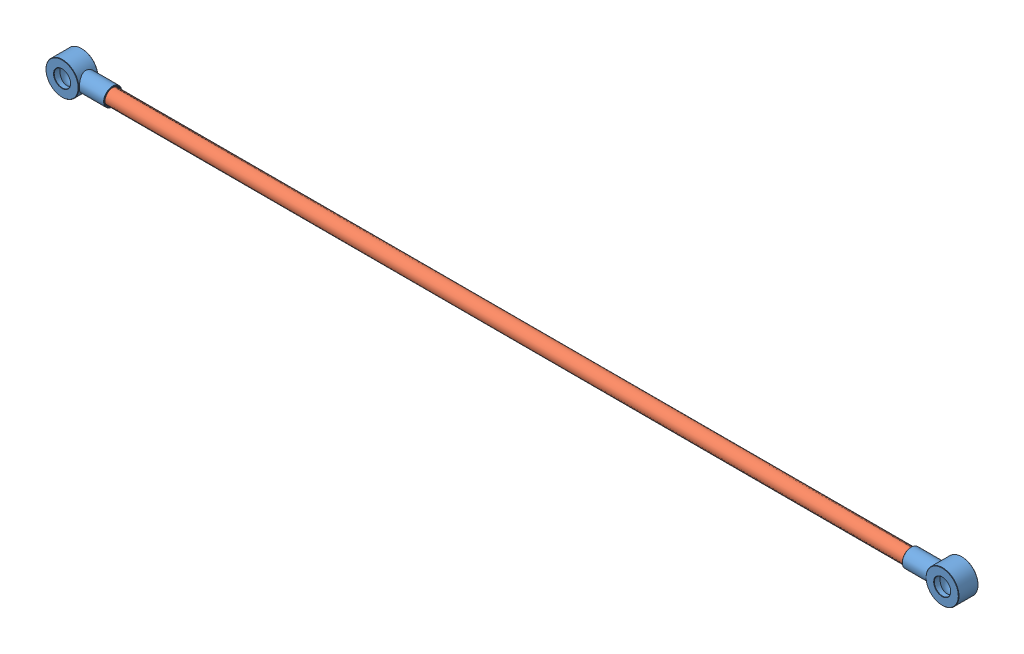
SolidWorks assembly Assem 4, configuration Default. Lengths in mm.
Overall size (2780 100 60).
3 component instances, 2 part files, 4 mates.
Components (placement in the parent):
- cylinder rod-1: cylinder rod [Default] at (487.3159 -1112.1844 -288.283) size (175 100 60)
- Fore arm-1: Fore arm [Default] at (577.3159 -1112.1844 -288.283) x (0 0 -1) z (1 0 0) size (45 45 2500)
- cylinder rod-2: cylinder rod [Default] at (3167.3159 -1112.1844 -288.283) x (-1 0 0) z (0 0 -1) size (175 100 60)
Mates (geometry in assembly coordinates):
- Concentric1: concentric anti-aligned: cylinder of cylinder rod-1 through (577.3159 -1112.1844 -288.283) axis (1 0 0) radius 23.5; cylinder of Fore arm-1 through (3077.3159 -1112.1844 -288.283) axis (-1 0 0) radius 22.5
- Coincident1: coincident anti-aligned: plane of cylinder rod-1 through (577.3159 -1112.1844 -288.283) normal (1 0 0); plane of Fore arm-1 through (577.3159 -1112.1844 -288.283) normal (-1 0 0)
- Concentric2: concentric aligned: cylinder of Fore arm-1 through (3077.3159 -1112.1844 -288.283) axis (-1 0 0) radius 22.5; cylinder of cylinder rod-2 through (3077.3159 -1112.1844 -288.283) axis (-1 0 0) radius 23.5
- Coincident2: coincident anti-aligned: plane of Fore arm-1 through (3077.3159 -1112.1844 -288.283) normal (1 0 0); plane of cylinder rod-2 through (3077.3159 -1112.1844 -288.283) normal (-1 0 0)
